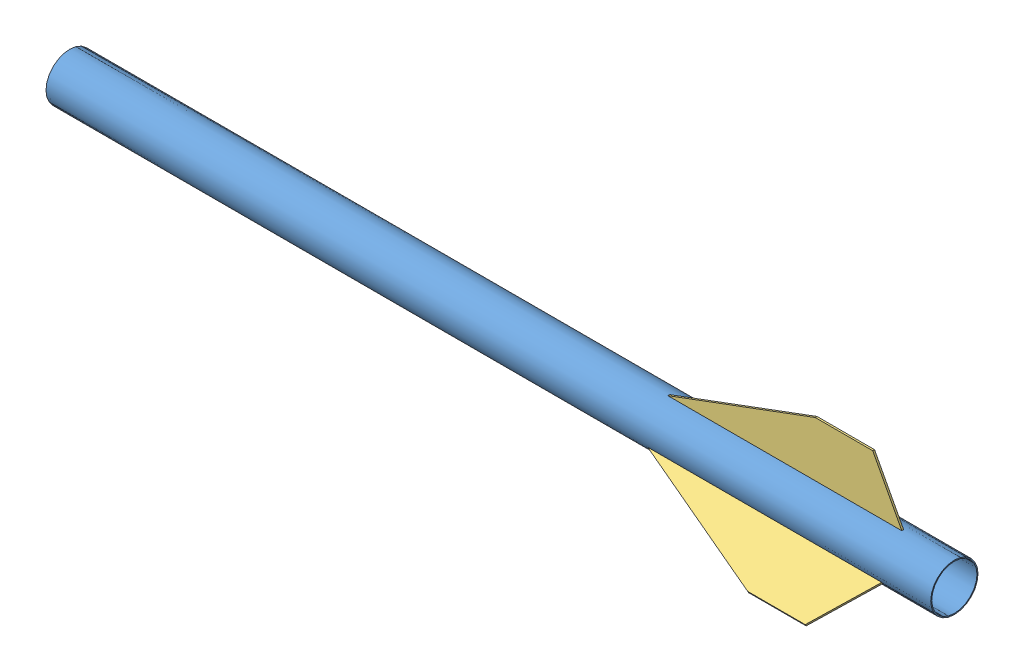
SolidWorks assembly MotorMount, configuration Default. Lengths in mm.
Overall size (762 102.03 117.81).
5 component instances, 3 part files, 11 mates.
Components (placement in the parent):
- 30InThinWallFiberglass-1: 30InThinWallFiberglass [Default] at origin size (762 40.74 40.74)
- InteriorMotorRetainer-1: InteriorMotorRetainer [Default] at (127 0 0) size (33.19 40.62 40.11)
- Fin-1: Fin [Default] at (515.9375 20.3708 -0.7874) size (201.61 47.19 1.57)
- Fin-2: Fin [Default] at (515.9375 -9.5035 18.0353) x (1 0 0) z (0 -0.866025 -0.5) size (201.61 47.19 1.57)
- Fin-3: Fin [Default] at (515.9375 -10.8673 -17.2479) x (1 0 0) z (0 0.866025 -0.5) size (201.61 47.19 1.57)
Mates (geometry in assembly coordinates):
- Concentric1: concentric aligned: cylinder of 30InThinWallFiberglass-1 through (762 0 0) axis (-1 0 0) radius 19.4818; cylinder of InteriorMotorRetainer-1 through (158.8516 0 0) axis (-1 0 0) radius 19.3167
- Distance1: distance = 127 mm aligned: plane of 30InThinWallFiberglass-1 through (0 0 0) normal (-1 0 0); plane of InteriorMotorRetainer-1 through (127 0 0) normal (-1 0 0)
- Tangent1: tangent anti-aligned: cylinder of 30InThinWallFiberglass-1 through (762 0 0) axis (-1 0 0) radius 20.3708; plane of Fin-1 through (515.9375 20.3708 0.7874) normal (0 -1 0)
- Distance2: distance = 44.45 mm: plane of 30InThinWallFiberglass-1 through (762 0 0) normal (1 0 0); line of Fin-1 through (717.55 20.3708 0.7874) axis (0 0 -1)
- Distance3: distance = 0.7874 mm: line of assembly; line of Fin-1 through (717.55 20.3708 -0.7874) axis (-0.469317 0.88303 0)
- Tangent4: tangent anti-aligned: cylinder of 30InThinWallFiberglass-1 through (762 0 0) axis (-1 0 0) radius 20.3708; plane of Fin-2 through (515.9375 -10.8673 17.2479) normal (0 0.5 -0.866025)
- Distance6: distance = 44.45 mm: line of Fin-2 through (717.55 -10.8673 17.2479) axis (0 0.866025 0.5); plane of 30InThinWallFiberglass-1 through (762 0 0) normal (1 0 0)
- Distance8: distance = 0.7874 mm: line of assembly; line of Fin-2 through (717.55 -9.5035 18.0353) axis (-0.469317 -0.441515 0.764726)
- Distance9: distance = 44.45 mm: line of Fin-3 through (717.55 -9.5035 -18.0353) axis (0 -0.866025 0.5); plane of 30InThinWallFiberglass-1 through (762 0 0) normal (1 0 0)
- Tangent6: tangent anti-aligned: cylinder of 30InThinWallFiberglass-1 through (762 0 0) axis (-1 0 0) radius 20.3708; plane of Fin-3 through (515.9375 -9.5035 -18.0353) normal (0 0.5 0.866025)
- Distance11: distance = 0.7874 mm: line of assembly; line of Fin-3 through (717.55 -9.5035 -18.0353) axis (-0.469317 -0.441515 -0.764726)
